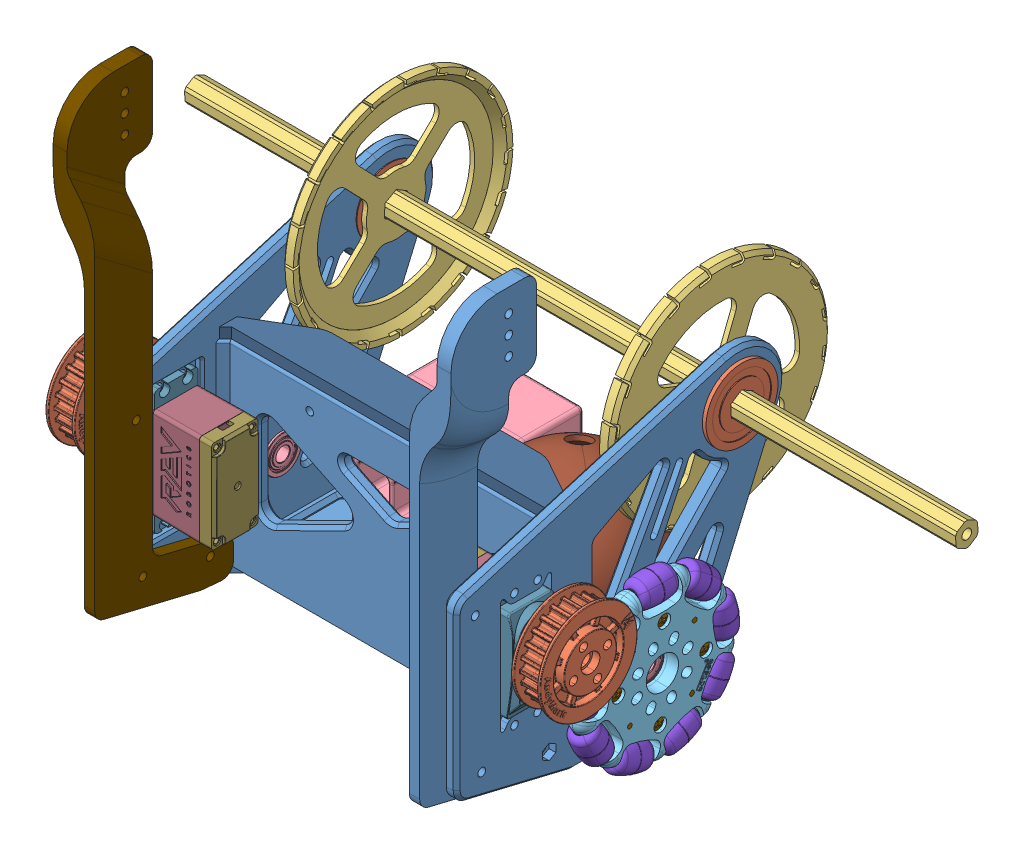
SolidWorks assembly Intake2RubberBand, configuration Default. Lengths in mm.
Overall size (333.38 218.44 194.34).
110 component instances, 23 part files, 83 mates.
Components (placement in the parent):
- IntakeWide-1: IntakeWide [Default] at (-43.2378 29.5162 123.384) size (157 122.29 142.09)
- 0_375_Hex_ID_x_1_125_OD_x_0_313_WD_Flanged_Bearing_217-2735 (1).step-1: 0_375_Hex_ID_x_1_125_OD_x_0_313_WD_Flanged_Bearing_217-2735 (1).step [Default] at (101.4122 125.5162 108.384) x (0 0.54174 -0.840546) z (0 -0.840546 -0.54174) size (31.12 7.94 31.12)
- 0_375_Hex_ID_x_1_125_OD_x_0_313_WD_Flanged_Bearing_217-2735 (1).step-2: 0_375_Hex_ID_x_1_125_OD_x_0_313_WD_Flanged_Bearing_217-2735 (1).step [Default] at (-42.8878 125.5162 108.384) x (0 0.998804 0.048888) z (0 -0.048888 0.998804) size (31.12 7.94 31.12)
- 375Hex13.3in-1: 375Hex13.3in [Default] at (-250.6814 125.5123 108.3763) x (0 0.54174 -0.840546) z (-1 0 0) size (10.24 9.53 333.38)
- 1601-0014-0006.step-1: 1601-0014-0006.step [Default] at (105.8122 54.5162 155.184) x (0 -0.381849 0.924225) z (0 -0.924225 -0.381849) size (15.95 5 15.95)
- 1601-0014-0006.step-2: 1601-0014-0006.step [Default] at (-47.2878 54.5162 155.184) x (0 -1 0) z (0 0 1) size (15.95 5 15.95)
- 3604-0014-0072 assembly.STEP-1: 3604-0014-0072 assembly.STEP [Default] at (98.0385 38.1974 184.2388) x (0 -0.339821 0.94049) z (0 0.94049 0.339821) size (78.59 16.98 77.39)
  - 3604-0014-0072 wheel half.STEP-1: 3604-0014-0072 wheel half.STEP [Default] at (-32.8712 13.6737 5.4742) size (67.84 5 66.97)
  - 3604-0014-0072 wheel half.STEP-2: 3604-0014-0072 wheel half.STEP [Default] at (-32.8712 23.6737 5.4742) x (-1 0 0) z (0 0 1) size (67.84 5 66.97)
  - 3604-0014-0072 bushing.STEP-1: 3604-0014-0072 bushing.STEP [Default] at (-52.1548 18.6737 -17.5071) x (-0.130318 0.979233 -0.155307) z (-0.766044 0 0.642788) size (5.61 5.61 17.1)
  - 3604-0014-0072 shaft.STEP-1: 3604-0014-0072 shaft.STEP [Default] at (-60.0068 18.6737 -10.9185) x (0.629069 0.205497 0.749695) z (-0.132091 0.978658 -0.15742) size (3.17 20.5 3.17)
  - 3604-0014-0072 roller.STEP-1: 3604-0014-0072 roller.STEP [Default] at (-52.1548 18.6737 -17.5071) x (-0.385664 0.800009 -0.459617) z (-0.766044 0 0.642788) size (12.13 12.13 16)
  - 3604-0014-0072 shaft.STEP-2: 3604-0014-0072 shaft.STEP [Default] at (-43.1212 18.6737 -24.5258) x (0 0.205497 0.978658) z (0 0.978658 -0.205497) size (3.17 20.5 3.17)
  - 3604-0014-0072 shaft.STEP-3: 3604-0014-0072 shaft.STEP [Default] at (-21.4395 18.6737 -24.0957) x (-0.629069 0.205497 0.749695) z (0.132091 0.978658 -0.15742) size (3.17 20.5 3.17)
  - 3604-0014-0072 shaft.STEP-4: 3604-0014-0072 shaft.STEP [Default] at (-5.1069 18.6737 -9.8295) x (-0.96379 0.205497 0.169942) z (0.202375 0.978658 -0.035684) size (3.17 20.5 3.17)
  - 3604-0014-0072 shaft.STEP-5: 3604-0014-0072 shaft.STEP [Default] at (-1.7654 18.6737 11.5975) x (-0.847543 0.205497 -0.489329) z (0.177965 0.978658 0.102748) size (3.17 20.5 3.17)
  - 3604-0014-0072 shaft.STEP-6: 3604-0014-0072 shaft.STEP [Default] at (-12.9787 18.6737 30.1593) x (-0.334721 0.205497 -0.919638) z (0.070284 0.978658 0.193104) size (3.17 20.5 3.17)
  - 3604-0014-0072 shaft.STEP-7: 3604-0014-0072 shaft.STEP [Default] at (-33.4999 18.6737 37.1707) x (0.334721 0.205497 -0.919638) z (-0.070284 0.978658 0.193104) size (3.17 20.5 3.17)
  - 3604-0014-0072 shaft.STEP-8: 3604-0014-0072 shaft.STEP [Default] at (-53.727 18.6737 29.351) x (0.847543 0.205497 -0.489329) z (-0.177965 0.978658 0.102748) size (3.17 20.5 3.17)
  - 3604-0014-0072 shaft.STEP-9: 3604-0014-0072 shaft.STEP [Default] at (-64.1953 18.6737 10.3591) x (0.96379 0.205497 0.169942) z (-0.202375 0.978658 -0.035684) size (3.17 20.5 3.17)
  - 3604-0014-0072 bushing.STEP-2: 3604-0014-0072 bushing.STEP [Default] at (-32.8712 18.6737 -24.5258) x (0 0.979233 -0.202739) z (-1 0 0) size (5.61 5.61 17.1)
  - 3604-0014-0072 bushing.STEP-3: 3604-0014-0072 bushing.STEP [Default] at (-13.5876 18.6737 -17.5071) x (0.130318 0.979233 -0.155307) z (-0.766044 0 -0.642788) size (5.61 5.61 17.1)
  - 3604-0014-0072 bushing.STEP-4: 3604-0014-0072 bushing.STEP [Default] at (-3.327 18.6737 0.2648) x (0.199659 0.979233 -0.035205) z (-0.173648 0 -0.984808) size (5.61 5.61 17.1)
  - 3604-0014-0072 bushing.STEP-5: 3604-0014-0072 bushing.STEP [Default] at (-6.8904 18.6737 20.4742) x (0.175577 0.979233 0.101369) z (0.5 0 -0.866025) size (5.61 5.61 17.1)
  - 3604-0014-0072 bushing.STEP-6: 3604-0014-0072 bushing.STEP [Default] at (-22.6106 18.6737 33.665) x (0.069341 0.979233 0.190512) z (0.939693 0 -0.34202) size (5.61 5.61 17.1)
  - 3604-0014-0072 bushing.STEP-7: 3604-0014-0072 bushing.STEP [Default] at (-43.1318 18.6737 33.665) x (-0.069341 0.979233 0.190512) z (0.939693 0 0.34202) size (5.61 5.61 17.1)
  - 3604-0014-0072 bushing.STEP-8: 3604-0014-0072 bushing.STEP [Default] at (-58.852 18.6737 20.4742) x (-0.175577 0.979233 0.101369) z (0.5 0 0.866025) size (5.61 5.61 17.1)
  - 3604-0014-0072 bushing.STEP-9: 3604-0014-0072 bushing.STEP [Default] at (-62.4154 18.6737 0.2648) x (-0.199659 0.979233 -0.035205) z (-0.173648 0 0.984808) size (5.61 5.61 17.1)
  - 3604-0014-0072 roller.STEP-2: 3604-0014-0072 roller.STEP [Default] at (-32.8712 18.6737 -24.5258) x (0 0.800009 -0.599987) z (-1 0 0) size (12.13 12.13 16)
  - 3604-0014-0072 roller.STEP-3: 3604-0014-0072 roller.STEP [Default] at (-13.5876 18.6737 -17.5071) x (0.385664 0.800009 -0.459617) z (-0.766044 0 -0.642788) size (12.13 12.13 16)
  - 3604-0014-0072 roller.STEP-4: 3604-0014-0072 roller.STEP [Default] at (-3.327 18.6737 0.2648) x (0.590872 0.800009 -0.104187) z (-0.173648 0 -0.984808) size (12.13 12.13 16)
  - 3604-0014-0072 roller.STEP-5: 3604-0014-0072 roller.STEP [Default] at (-6.8904 18.6737 20.4742) x (0.519604 0.800009 0.299994) z (0.5 0 -0.866025) size (12.13 12.13 16)
  - 3604-0014-0072 roller.STEP-6: 3604-0014-0072 roller.STEP [Default] at (-22.6106 18.6737 33.665) x (0.205208 0.800009 0.563804) z (0.939693 0 -0.34202) size (12.13 12.13 16)
  - 3604-0014-0072 roller.STEP-7: 3604-0014-0072 roller.STEP [Default] at (-43.1318 18.6737 33.665) x (-0.205208 0.800009 0.563804) z (0.939693 0 0.34202) size (12.13 12.13 16)
  - 3604-0014-0072 roller.STEP-8: 3604-0014-0072 roller.STEP [Default] at (-58.852 18.6737 20.4742) x (-0.519604 0.800009 0.299994) z (0.5 0 0.866025) size (12.13 12.13 16)
  - 3604-0014-0072 roller.STEP-9: 3604-0014-0072 roller.STEP [Default] at (-62.4154 18.6737 0.2648) x (-0.590872 0.800009 -0.104187) z (-0.173648 0 0.984808) size (12.13 12.13 16)
  - 364 omni wheel screw_99461A110.STEP-1: 364 omni wheel screw_99461A110.STEP [Default] at (-40.1422 17.6737 23.0279) x (1 0 0) z (0 1 0) size (5.22 5.22 9.61)
  - 364 omni wheel screw_99461A110.STEP-2: 364 omni wheel screw_99461A110.STEP [Default] at (-50.4249 17.6737 -1.7968) x (0 0 1) z (0 1 0) size (5.22 5.22 9.61)
  - 364 omni wheel screw_99461A110.STEP-3: 364 omni wheel screw_99461A110.STEP [Default] at (-25.6002 17.6737 -12.0795) x (-1 0 0) z (0 1 0) size (5.22 5.22 9.61)
  - 364 omni wheel screw_99461A110.STEP-4: 364 omni wheel screw_99461A110.STEP [Default] at (-15.3175 17.6737 12.7452) x (0 0 -1) z (0 1 0) size (5.22 5.22 9.61)
  - 364 omni wheel screw_99461A110.STEP-5: 364 omni wheel screw_99461A110.STEP [Default] at (-25.6002 19.6737 23.0279) x (-0.837169 0 -0.546944) z (0 -1 0) size (5.22 5.22 9.61)
  - 364 omni wheel screw_99461A110.STEP-6: 364 omni wheel screw_99461A110.STEP [Default] at (-15.3175 19.6737 -1.7968) x (-0.546944 0 0.837169) z (0 -1 0) size (5.22 5.22 9.61)
  - 364 omni wheel screw_99461A110.STEP-7: 364 omni wheel screw_99461A110.STEP [Default] at (-40.1422 19.6737 -12.0795) x (0.837169 0 0.546944) z (0 -1 0) size (5.22 5.22 9.61)
  - 364 omni wheel screw_99461A110.STEP-8: 364 omni wheel screw_99461A110.STEP [Default] at (-50.4249 19.6737 12.7452) x (0.546944 0 -0.837169) z (0 -1 0) size (5.22 5.22 9.61)
- 1601-0014-0006.step-6: 1601-0014-0006.step [Default] at (115.7622 54.5162 155.184) x (0 -0.381849 0.924225) z (0 -0.924225 -0.381849) size (15.95 5 15.95)
- 1601-0014-0006.step-8: 1601-0014-0006.step [Default] at (-58.1878 54.5162 155.184) x (0 0.206987 0.978344) z (0 -0.978344 0.206987) size (15.95 5 15.95)
- 3604-0014-0072 assembly.STEP-2: 3604-0014-0072 assembly.STEP [Default] at (-75.9115 38.6322 184.4787) x (0 -0.32577 0.945449) z (0 0.945449 0.32577) size (78.59 16.98 77.39)
  - 3604-0014-0072 wheel half.STEP-1: 3604-0014-0072 wheel half.STEP [Default] at (-32.8712 13.6737 5.4742) size (67.84 5 66.97)
  - 3604-0014-0072 wheel half.STEP-2: 3604-0014-0072 wheel half.STEP [Default] at (-32.8712 23.6737 5.4742) x (-1 0 0) z (0 0 1) size (67.84 5 66.97)
  - 3604-0014-0072 bushing.STEP-1: 3604-0014-0072 bushing.STEP [Default] at (-52.1548 18.6737 -17.5071) x (-0.130318 0.979233 -0.155307) z (-0.766044 0 0.642788) size (5.61 5.61 17.1)
  - 3604-0014-0072 shaft.STEP-1: 3604-0014-0072 shaft.STEP [Default] at (-60.0068 18.6737 -10.9185) x (0.629069 0.205497 0.749695) z (-0.132091 0.978658 -0.15742) size (3.17 20.5 3.17)
  - 3604-0014-0072 roller.STEP-1: 3604-0014-0072 roller.STEP [Default] at (-52.1548 18.6737 -17.5071) x (-0.385664 0.800009 -0.459617) z (-0.766044 0 0.642788) size (12.13 12.13 16)
  - 3604-0014-0072 shaft.STEP-2: 3604-0014-0072 shaft.STEP [Default] at (-43.1212 18.6737 -24.5258) x (0 0.205497 0.978658) z (0 0.978658 -0.205497) size (3.17 20.5 3.17)
  - 3604-0014-0072 shaft.STEP-3: 3604-0014-0072 shaft.STEP [Default] at (-21.4395 18.6737 -24.0957) x (-0.629069 0.205497 0.749695) z (0.132091 0.978658 -0.15742) size (3.17 20.5 3.17)
  - 3604-0014-0072 shaft.STEP-4: 3604-0014-0072 shaft.STEP [Default] at (-5.1069 18.6737 -9.8295) x (-0.96379 0.205497 0.169942) z (0.202375 0.978658 -0.035684) size (3.17 20.5 3.17)
  - 3604-0014-0072 shaft.STEP-5: 3604-0014-0072 shaft.STEP [Default] at (-1.7654 18.6737 11.5975) x (-0.847543 0.205497 -0.489329) z (0.177965 0.978658 0.102748) size (3.17 20.5 3.17)
  - 3604-0014-0072 shaft.STEP-6: 3604-0014-0072 shaft.STEP [Default] at (-12.9787 18.6737 30.1593) x (-0.334721 0.205497 -0.919638) z (0.070284 0.978658 0.193104) size (3.17 20.5 3.17)
  - 3604-0014-0072 shaft.STEP-7: 3604-0014-0072 shaft.STEP [Default] at (-33.4999 18.6737 37.1707) x (0.334721 0.205497 -0.919638) z (-0.070284 0.978658 0.193104) size (3.17 20.5 3.17)
  - 3604-0014-0072 shaft.STEP-8: 3604-0014-0072 shaft.STEP [Default] at (-53.727 18.6737 29.351) x (0.847543 0.205497 -0.489329) z (-0.177965 0.978658 0.102748) size (3.17 20.5 3.17)
  - 3604-0014-0072 shaft.STEP-9: 3604-0014-0072 shaft.STEP [Default] at (-64.1953 18.6737 10.3591) x (0.96379 0.205497 0.169942) z (-0.202375 0.978658 -0.035684) size (3.17 20.5 3.17)
  - 3604-0014-0072 bushing.STEP-2: 3604-0014-0072 bushing.STEP [Default] at (-32.8712 18.6737 -24.5258) x (0 0.979233 -0.202739) z (-1 0 0) size (5.61 5.61 17.1)
  - 3604-0014-0072 bushing.STEP-3: 3604-0014-0072 bushing.STEP [Default] at (-13.5876 18.6737 -17.5071) x (0.130318 0.979233 -0.155307) z (-0.766044 0 -0.642788) size (5.61 5.61 17.1)
  - 3604-0014-0072 bushing.STEP-4: 3604-0014-0072 bushing.STEP [Default] at (-3.327 18.6737 0.2648) x (0.199659 0.979233 -0.035205) z (-0.173648 0 -0.984808) size (5.61 5.61 17.1)
  - 3604-0014-0072 bushing.STEP-5: 3604-0014-0072 bushing.STEP [Default] at (-6.8904 18.6737 20.4742) x (0.175577 0.979233 0.101369) z (0.5 0 -0.866025) size (5.61 5.61 17.1)
  - 3604-0014-0072 bushing.STEP-6: 3604-0014-0072 bushing.STEP [Default] at (-22.6106 18.6737 33.665) x (0.069341 0.979233 0.190512) z (0.939693 0 -0.34202) size (5.61 5.61 17.1)
  - 3604-0014-0072 bushing.STEP-7: 3604-0014-0072 bushing.STEP [Default] at (-43.1318 18.6737 33.665) x (-0.069341 0.979233 0.190512) z (0.939693 0 0.34202) size (5.61 5.61 17.1)
  - 3604-0014-0072 bushing.STEP-8: 3604-0014-0072 bushing.STEP [Default] at (-58.852 18.6737 20.4742) x (-0.175577 0.979233 0.101369) z (0.5 0 0.866025) size (5.61 5.61 17.1)
  - 3604-0014-0072 bushing.STEP-9: 3604-0014-0072 bushing.STEP [Default] at (-62.4154 18.6737 0.2648) x (-0.199659 0.979233 -0.035205) z (-0.173648 0 0.984808) size (5.61 5.61 17.1)
  - 3604-0014-0072 roller.STEP-2: 3604-0014-0072 roller.STEP [Default] at (-32.8712 18.6737 -24.5258) x (0 0.800009 -0.599987) z (-1 0 0) size (12.13 12.13 16)
  - 3604-0014-0072 roller.STEP-3: 3604-0014-0072 roller.STEP [Default] at (-13.5876 18.6737 -17.5071) x (0.385664 0.800009 -0.459617) z (-0.766044 0 -0.642788) size (12.13 12.13 16)
  - 3604-0014-0072 roller.STEP-4: 3604-0014-0072 roller.STEP [Default] at (-3.327 18.6737 0.2648) x (0.590872 0.800009 -0.104187) z (-0.173648 0 -0.984808) size (12.13 12.13 16)
  - 3604-0014-0072 roller.STEP-5: 3604-0014-0072 roller.STEP [Default] at (-6.8904 18.6737 20.4742) x (0.519604 0.800009 0.299994) z (0.5 0 -0.866025) size (12.13 12.13 16)
  - 3604-0014-0072 roller.STEP-6: 3604-0014-0072 roller.STEP [Default] at (-22.6106 18.6737 33.665) x (0.205208 0.800009 0.563804) z (0.939693 0 -0.34202) size (12.13 12.13 16)
  - 3604-0014-0072 roller.STEP-7: 3604-0014-0072 roller.STEP [Default] at (-43.1318 18.6737 33.665) x (-0.205208 0.800009 0.563804) z (0.939693 0 0.34202) size (12.13 12.13 16)
  - 3604-0014-0072 roller.STEP-8: 3604-0014-0072 roller.STEP [Default] at (-58.852 18.6737 20.4742) x (-0.519604 0.800009 0.299994) z (0.5 0 0.866025) size (12.13 12.13 16)
  - 3604-0014-0072 roller.STEP-9: 3604-0014-0072 roller.STEP [Default] at (-62.4154 18.6737 0.2648) x (-0.590872 0.800009 -0.104187) z (-0.173648 0 0.984808) size (12.13 12.13 16)
  - 364 omni wheel screw_99461A110.STEP-1: 364 omni wheel screw_99461A110.STEP [Default] at (-40.1422 17.6737 23.0279) x (1 0 0) z (0 1 0) size (5.22 5.22 9.61)
  - 364 omni wheel screw_99461A110.STEP-2: 364 omni wheel screw_99461A110.STEP [Default] at (-50.4249 17.6737 -1.7968) x (0 0 1) z (0 1 0) size (5.22 5.22 9.61)
  - 364 omni wheel screw_99461A110.STEP-3: 364 omni wheel screw_99461A110.STEP [Default] at (-25.6002 17.6737 -12.0795) x (-1 0 0) z (0 1 0) size (5.22 5.22 9.61)
  - 364 omni wheel screw_99461A110.STEP-4: 364 omni wheel screw_99461A110.STEP [Default] at (-15.3175 17.6737 12.7452) x (0 0 -1) z (0 1 0) size (5.22 5.22 9.61)
  - 364 omni wheel screw_99461A110.STEP-5: 364 omni wheel screw_99461A110.STEP [Default] at (-25.6002 19.6737 23.0279) x (-0.837169 0 -0.546944) z (0 -1 0) size (5.22 5.22 9.61)
  - 364 omni wheel screw_99461A110.STEP-6: 364 omni wheel screw_99461A110.STEP [Default] at (-15.3175 19.6737 -1.7968) x (-0.546944 0 0.837169) z (0 -1 0) size (5.22 5.22 9.61)
  - 364 omni wheel screw_99461A110.STEP-7: 364 omni wheel screw_99461A110.STEP [Default] at (-40.1422 19.6737 -12.0795) x (0.837169 0 0.546944) z (0 -1 0) size (5.22 5.22 9.61)
  - 364 omni wheel screw_99461A110.STEP-8: 364 omni wheel screw_99461A110.STEP [Default] at (-50.4249 19.6737 12.7452) x (0.546944 0 -0.837169) z (0 -1 0) size (5.22 5.22 9.61)
- RubberBandRoof-1: RubberBandRoof [Default] at (-43.2378 110.5162 123.384) x (1 0 0) z (0 1 0) size (145 22 18.5)
- am-2850 wiffle base Ball.step-1: am-2850 wiffle base Ball.step [Default] at (66.2022 65.0762 138.624) x (0.76558 0.27445 0.581863) z (-0.623857 0.095806 0.775644) size (71.12 71.12 71.12)
- REV-41-1097.STEP-1: REV-41-1097.STEP [Default] at (-16.8878 77.7662 200.1841) x (0 0 1) z (1 0 0) size (24.05 54 43.73)
  - A.STEP-1: A.STEP [Default] at origin size (20.15 40.13 8.54)
  - E.STEP-1: E.STEP [Default] at origin size (20.15 40.15 20.1)
  - C.STEP-1: C.STEP [Default] at origin size (24.05 54 13.28)
  - B.STEP-1: B.STEP [Default] at origin size (9 9 4.4)
  - D.STEP-1: D.STEP [Default] at (0 -10.0526 -30.1) x (-1 0 0) z (0 0 1) size (17.21 17.2 14.7)
- REV-41-1097.STEP-2: REV-41-1097.STEP [Default] at (75.4122 77.7662 200.1835) x (0 0 -1) z (-1 0 0) size (24.05 54 43.73)
  - A.STEP-1: A.STEP [Default] at origin size (20.15 40.13 8.54)
  - E.STEP-1: E.STEP [Default] at origin size (20.15 40.15 20.1)
  - C.STEP-1: C.STEP [Default] at origin size (24.05 54 13.28)
  - B.STEP-1: B.STEP [Default] at origin size (9 9 4.4)
  - D.STEP-1: D.STEP [Default] at (0 -10.0526 -30.1) x (-1 0 0) z (0 0 1) size (17.21 17.2 14.7)
- IntakeServoHorn-1: IntakeServoHorn [Default] at (-58.5878 87.8188 200.1841) x (0 0.715777 -0.698329) z (0 0.698329 0.715777) size (25 6 25)
- IntakeServoHorn-2: IntakeServoHorn [Default] at (117.1122 87.8188 200.1835) x (0 0.059406 -0.998234) z (0 -0.998234 -0.059406) size (25 6 25)
- Part2^Intake2RubberBand-1: Part2^Intake2RubberBand [Default] at (-43.2378 29.5162 123.384) x (0 0 -1) z (1 0 0) size (60 201.86 19.65) (virtual)
- IntakeArm2Mir-1: IntakeArm2Mir [Default] at (92.7622 29.5162 123.384) x (0 0 -1) z (1 0 0) size (60 201.86 19.65)
- am-3401+24+tooth+HTD+pulley+half+6mm+bore-1: am-3401+24+tooth+HTD+pulley+half+6mm+bore [Default] at (-70.0903 76.941 175.3595) x (-1 0 0) z (0 -0.924225 -0.381849) size (8.91 42 42)
- am-3401+24+tooth+HTD+pulley+half+6mm+bore-2: am-3401+24+tooth+HTD+pulley+half+6mm+bore [Default] at (-70.0903 60.9034 214.1769) x (1 0 0) z (0 -0.924225 -0.381849) size (8.91 42 42)
- am-3401+24+tooth+HTD+pulley+half+6mm+bore-3: am-3401+24+tooth+HTD+pulley+half+6mm+bore [Default] at (128.6147 60.3913 211.5733) x (1 0 0) z (0 -0.924225 -0.381849) size (8.91 42 42)
- am-3401+24+tooth+HTD+pulley+half+6mm+bore-4: am-3401+24+tooth+HTD+pulley+half+6mm+bore [Default] at (128.6147 76.4289 172.7559) x (-1 0 0) z (0 -0.924225 -0.381849) size (8.91 42 42)
- Part1^Intake2RubberBand-1: Part1^Intake2RubberBand [Default] at origin (virtual)
- IntakeBandWheel-1: IntakeBandWheel [Default] at (100.2333 125.5162 108.384) x (-1 0 0) z (0 -0.91644 -0.400173) size (5 94.99 94.99)
- IntakeBandWheel-2: IntakeBandWheel [Default] at (-42.2378 125.5162 108.384) x (1 0 0) z (0 0.019908 0.999802) size (5 94.99 94.99)
- ftc-2013 2in Cube.step-2: ftc-2013 2in Cube.step [Default] at (5.2422 54.9162 123.3042) size (50.8 50.8 50.94)
Mates (geometry in assembly coordinates):
- Concentric1: concentric: cylinder of IntakeWide-1 through (101.7622 125.5162 108.384) axis (1 0 0) radius 14.2875; cylinder of 0_375_Hex_ID_x_1_125_OD_x_0_313_WD_Flanged_Bearing_217-2735 (1).step-1 through (101.4122 125.5162 108.384) axis (1 0 0) radius 14.2748
- Coincident1: coincident: plane of IntakeWide-1 through (107.7622 23.5162 174.184) normal (1 0 0); plane of 0_375_Hex_ID_x_1_125_OD_x_0_313_WD_Flanged_Bearing_217-2735 (1).step-1 through (107.7622 133.9444 95.3072) normal (-1 0 0)
- Concentric2: concentric: cylinder of IntakeWide-1 through (-43.2378 125.5162 108.384) axis (-1 0 0) radius 14.2875; cylinder of 0_375_Hex_ID_x_1_125_OD_x_0_313_WD_Flanged_Bearing_217-2735 (1).step-2 through (-42.8878 125.5162 108.384) axis (-1 0 0) radius 14.2748
- Coincident2: coincident: plane of IntakeWide-1 through (-49.2378 23.5162 174.184) normal (-1 0 0); plane of 0_375_Hex_ID_x_1_125_OD_x_0_313_WD_Flanged_Bearing_217-2735 (1).step-2 through (-49.2378 141.0551 109.1446) normal (1 0 0)
- Coincident3: coincident: plane of 0_375_Hex_ID_x_1_125_OD_x_0_313_WD_Flanged_Bearing_217-2735 (1).step-1 through (127.3102 122.9988 103.4851) normal (0 0.840546 0.54174); plane of 375Hex13.3in-1 through (-707.8814 122.9988 103.4851) normal (0 -0.840546 -0.54174)
- Coincident4: coincident: plane of 0_375_Hex_ID_x_1_125_OD_x_0_313_WD_Flanged_Bearing_217-2735 (1).step-2 through (-68.7858 120.0149 108.1147) normal (0 0.840546 0.54174); plane of 375Hex13.3in-1 through (-707.8814 122.9988 103.4851) normal (0 -0.840546 -0.54174)
- Coincident5: coincident: plane of 0_375_Hex_ID_x_1_125_OD_x_0_313_WD_Flanged_Bearing_217-2735 (1).step-1 through (127.3102 128.5001 103.7544) normal (0 -0.048888 0.998804); plane of 375Hex13.3in-1 through (-707.8814 128.4914 103.7539) normal (0 0.048888 -0.998804)
- Concentric3: concentric: cylinder of IntakeWide-1 through (-49.2378 54.5162 155.184) axis (1 0 0) radius 7.05; cylinder of 1601-0014-0006.step-1 through (101.7622 54.5162 155.184) axis (1 0 0) radius 7
- Coincident6: coincident: plane of IntakeWide-1 through (101.7622 29.5162 174.184) normal (-1 0 0); plane of 1601-0014-0006.step-1 through (101.7622 54.5162 155.184) normal (1 0 0)
- Coincident7: coincident: plane of IntakeWide-1 through (-43.2378 29.5162 174.184) normal (1 0 0); plane of 1601-0014-0006.step-2 through (-43.2378 54.5162 155.184) normal (-1 0 0)
- Concentric4: concentric: cylinder of IntakeWide-1 through (-49.2378 54.5162 155.184) axis (1 0 0) radius 7.05; cylinder of 1601-0014-0006.step-2 through (-43.2378 54.5162 155.184) axis (-1 0 0) radius 7
- Coincident8: coincident: circle of 3604-0014-0072 assembly.STEP-1/3604-0014-0072 wheel half.STEP-2; cylinder of ? through (121.7122 54.5162 155.184) axis (-1 0 0) radius 7
- Coincident9: coincident: plane of 3604-0014-0072 assembly.STEP-1/3604-0014-0072 wheel half.STEP-2 through (121.7122 54.5162 155.184) normal (1 0 0); plane of ? through (121.7122 54.5162 155.184) normal (-1 0 0)
- Concentric5: concentric: cylinder of 3604-0014-0072 assembly.STEP-1/3604-0014-0072 wheel half.STEP-1 through (111.7122 54.5162 155.184) axis (1 0 0) radius 7; cylinder of 1601-0014-0006.step-6 through (111.7122 54.5162 155.184) axis (1 0 0) radius 7
- Coincident10: coincident: plane of 3604-0014-0072 assembly.STEP-1/3604-0014-0072 wheel half.STEP-1 through (111.7122 54.5162 155.184) normal (-1 0 0); plane of 1601-0014-0006.step-6 through (111.7122 54.5162 155.184) normal (1 0 0)
- Concentric6: concentric: cylinder of 1601-0014-0006.step-1 through (105.8122 54.5162 155.184) axis (-1 0 0) radius 3; cylinder of ? through (117.6622 54.5162 155.184) axis (1 0 0) radius 3
- Distance2: distance = 3 mm: plane of 1601-0014-0006.step-6 through (110.7622 54.5162 155.184) normal (-1 0 0); plane of IntakeWide-1 through (107.7622 23.5162 174.184) normal (1 0 0)
- Concentric7: concentric: cylinder of ? through (-62.2378 54.5162 155.184) axis (1 0 0) radius 7; cylinder of 3604-0014-0072 assembly.STEP-2/3604-0014-0072 wheel half.STEP-1 through (-62.2378 54.5162 155.184) axis (1 0 0) radius 7
- Coincident13: coincident: cylinder of 1601-0014-0006.step-8 through (-62.2378 54.5162 155.184) axis (1 0 0) radius 7; circle of 3604-0014-0072 assembly.STEP-2/3604-0014-0072 wheel half.STEP-2
- Coincident14: coincident: plane of 1601-0014-0006.step-8 through (-62.2378 54.5162 155.184) normal (1 0 0); plane of 3604-0014-0072 assembly.STEP-2/3604-0014-0072 wheel half.STEP-1 through (-62.2378 54.5162 155.184) normal (-1 0 0)
- Coincident15: coincident: plane of ? through (-62.2378 54.5162 155.184) normal (1 0 0); plane of 3604-0014-0072 assembly.STEP-2/3604-0014-0072 wheel half.STEP-1 through (-62.2378 54.5162 155.184) normal (-1 0 0)
- Concentric8: concentric: cylinder of 1601-0014-0006.step-2 through (-47.2878 54.5162 155.184) axis (1 0 0) radius 3; cylinder of ? through (-58.1878 54.5162 155.184) axis (-1 0 0) radius 3
- Distance3: distance = 3 mm: plane of 3604-0014-0072 assembly.STEP-2/3604-0014-0072 wheel half.STEP-2 through (-52.2378 54.5162 155.184) normal (1 0 0); plane of IntakeWide-1 through (-49.2378 23.5162 174.184) normal (-1 0 0)
- Coincident17: coincident: plane of 375Hex13.3in-1 through (-707.8814 128.4914 103.7539) normal (0 0.048888 -0.998804); plane of ? through (79.2622 128.4914 103.7539) normal (0 -0.048888 0.998804)
- Coincident18: coincident: plane of 375Hex13.3in-1 through (-707.8814 122.9988 103.4851) normal (0 -0.840546 -0.54174); plane of ? through (79.2622 122.9988 103.4851) normal (0 0.840546 0.54174)
- Coincident19: coincident: plane of 375Hex13.3in-1 through (-707.8814 122.5331 112.9987) normal (0 -0.048888 0.998804); plane of ? through (39.2622 122.5331 112.9987) normal (0 0.048888 -0.998804)
- Coincident20: coincident: plane of 375Hex13.3in-1 through (-707.8814 122.5331 112.9987) normal (0 -0.048888 0.998804); plane of ? through (-0.7378 122.5331 112.9987) normal (0 0.048888 -0.998804)
- Coincident21: coincident: plane of 375Hex13.3in-1 through (-707.8814 122.5331 112.9987) normal (0 -0.048888 0.998804); plane of ? through (-40.7378 122.5331 112.9987) normal (0 0.048888 -0.998804)
- Coincident22: coincident: plane of 375Hex13.3in-1 through (-707.8814 128.0258 113.2675) normal (0 0.840546 0.54174); plane of ? through (39.2622 128.0258 113.2675) normal (0 -0.840546 -0.54174)
- Coincident23: coincident: plane of 375Hex13.3in-1 through (-707.8814 128.0258 113.2675) normal (0 0.840546 0.54174); plane of ? through (-0.7378 128.0258 113.2675) normal (0 -0.840546 -0.54174)
- Coincident24: coincident: plane of 375Hex13.3in-1 through (-707.8814 122.9988 103.4851) normal (0 -0.840546 -0.54174); plane of ? through (-40.7378 122.9988 103.4851) normal (0 0.840546 0.54174)
- Distance4: distance = 20 mm: plane of ? through (59.2622 125.5123 108.3763) normal (1 0 0); plane of ? through (79.2622 125.5123 108.3763) normal (-1 0 0)
- Distance5: distance = 20 mm: plane of ? through (39.2622 125.5123 108.3763) normal (-1 0 0); plane of ? through (19.2622 125.5123 108.3763) normal (1 0 0)
- Distance6: distance = 20 mm: plane of ? through (-20.7378 125.5123 108.3763) normal (1 0 0); plane of ? through (-0.7378 125.5123 108.3763) normal (-1 0 0)
- Distance7: distance = 2.5 mm: plane of IntakeWide-1 through (101.7622 29.5162 174.184) normal (-1 0 0); plane of ? through (99.2622 125.5123 108.3763) normal (1 0 0)
- InPlace1: in place: plane of IntakeWide-1 through (-49.2378 110.5162 174.184) normal (0 1 0); plane of ? through (0 110.5162 0) normal (0 1 0); moOrthogonalPlaneRef_w of IntakeWide-1 through (-49.2378 110.5162 174.184) normal (0 1 0); plane of ? through (0 110.5162 0) normal (0 0 -1); plane of IntakeWide-1 through (-49.2378 110.5162 174.184) normal (0 1 0); plane of ? through (0 110.5162 0) normal (1 0 0); plane of IntakeWide-1 through (-49.2378 110.5162 174.184) normal (0 1 0); unknown of RubberBandRoof-1
- Coincident29: coincident: plane of IntakeWide-1; plane of RubberBandRoof-1
- Coincident30: coincident: moOrthogonalPlaneRef_w of IntakeWide-1 through (-43.2378 110.5162 123.384) normal (0 0 -1); plane of RubberBandRoof-1 through (-43.2378 110.5162 123.384) normal (0 0 -1)
- Coincident31: coincident: moOrthogonalPlaneRef_w of IntakeWide-1 through (-43.2378 110.5162 123.384) normal (-1 0 0); plane of RubberBandRoof-1 through (-43.2378 110.5162 123.384) normal (1 0 0)
- Tangent1: tangent: plane of IntakeWide-1 through (-43.2378 29.5162 174.184) normal (0 1 0); sphere of am-2850 wiffle base Ball.step-1
- Tangent2: tangent: plane of IntakeWide-1 through (-43.2378 29.5162 174.184) normal (0 0 -1); sphere of am-2850 wiffle base Ball.step-1
- Tangent3: tangent: plane of IntakeWide-1 through (101.7622 29.5162 174.184) normal (-1 0 0); sphere of am-2850 wiffle base Ball.step-1
- Coincident32: coincident: plane of IntakeWide-1 through (-43.2378 29.5162 174.184) normal (0 1 0); plane of ? through (27.6547 29.5162 120.384) normal (0 -1 0)
- Distance8: distance = 3 mm: plane of ? through (-23.1453 80.3162 171.184) normal (0 0 1); plane of IntakeWide-1 through (-43.2378 29.5162 174.184) normal (0 0 -1)
- Concentric9: concentric: cylinder of IntakeWide-1 through (-43.2378 102.5162 205.1841) axis (-1 0 0) radius 1.65; cylinder of REV-41-1097.STEP-1/C.STEP-1 through (-46.2378 102.5162 205.1841) axis (-1 0 0) radius 2.25
- Concentric10: concentric: cylinder of IntakeWide-1 through (-43.2378 102.5162 195.1835) axis (-1 0 0) radius 1.65; cylinder of REV-41-1097.STEP-1/C.STEP-1 through (-46.2378 102.5162 195.1841) axis (-1 0 0) radius 2.25
- Concentric11: concentric: cylinder of IntakeWide-1 through (101.7622 102.5162 195.1835) axis (1 0 0) radius 1.65; cylinder of REV-41-1097.STEP-2/C.STEP-1 through (104.7622 102.5162 195.1835) axis (1 0 0) radius 2.25
- Concentric12: concentric: cylinder of IntakeWide-1 through (101.7622 102.5162 205.1841) axis (1 0 0) radius 1.65; cylinder of REV-41-1097.STEP-2/C.STEP-1 through (104.7622 102.5162 205.1835) axis (1 0 0) radius 2.25
- Coincident34: coincident: plane of IntakeWide-1 through (104.7622 29.5162 123.384) normal (-1 0 0); plane of REV-41-1097.STEP-2/C.STEP-1 through (104.7622 77.7662 200.1835) normal (1 0 0)
- Concentric13: concentric: circle of REV-41-1097.STEP-1/D.STEP-1; cylinder of IntakeServoHorn-1 through (-63.0878 87.8188 200.1841) axis (1 0 0) radius 1.75
- Coincident35: coincident: plane of REV-41-1097.STEP-1/D.STEP-1 through (-60.5878 87.8188 200.1841) normal (-1 0 0); plane of IntakeServoHorn-1 through (-60.5878 87.8188 200.1841) normal (1 0 0)
- Concentric14: concentric: circle of REV-41-1097.STEP-2/D.STEP-1; cylinder of IntakeServoHorn-2 through (119.1122 87.8188 200.1835) axis (1 0 0) radius 12.5
- Coincident36: coincident: plane of REV-41-1097.STEP-2/D.STEP-1 through (119.1122 87.8188 200.1835) normal (1 0 0); plane of IntakeServoHorn-2 through (119.1122 87.8188 200.1835) normal (-1 0 0)
- BeltMate1: belt = 4.2 : 25 mm: circle of IntakeServoHorn-1; cylinder of 375Hex13.3in-1 through (206.5186 125.5123 108.3763) axis (-1 0 0) radius 2.1
- InPlace2: in place: plane of IntakeWide-1 through (-43.2378 29.5162 174.184) normal (1 0 0); plane of ? through (-43.2378 0 0) normal (1 0 0); plane of IntakeWide-1 through (-43.2378 29.5162 174.184) normal (1 0 0); plane of ? through (-43.2378 0 0) normal (0 1 0); plane of IntakeWide-1 through (-43.2378 29.5162 174.184) normal (1 0 0); plane of ? through (-43.2378 0 0) normal (0 0 -1); plane of IntakeWide-1 through (-43.2378 29.5162 174.184) normal (1 0 0); unknown of Part2^Intake2RubberBand-1
- Coincident37: coincident: plane of IntakeWide-1; plane of ?
- Coincident38: coincident: moOrthogonalPlaneRef_w of IntakeWide-1 through (-43.2378 29.5162 123.384) normal (0 1 0); plane of Part2^Intake2RubberBand-1 through (-43.2378 29.5162 123.384) normal (0 1 0)
- Coincident39: coincident: moOrthogonalPlaneRef_w of IntakeWide-1 through (-43.2378 29.5162 123.384) normal (0 0 1); plane of Part2^Intake2RubberBand-1 through (-43.2378 29.5162 123.384) normal (0 0 -1)
- InPlace3: in place: plane of IntakeWide-1 through (-43.2378 29.5162 174.184) normal (1 0 0); plane of ? through (-43.2378 0 0) normal (1 0 0); plane of IntakeWide-1 through (-43.2378 29.5162 174.184) normal (1 0 0); plane of ? through (-43.2378 0 0) normal (0 1 0); plane of IntakeWide-1 through (-43.2378 29.5162 174.184) normal (1 0 0); plane of ? through (-43.2378 0 0) normal (0 0 -1); plane of IntakeWide-1 through (-43.2378 29.5162 174.184) normal (1 0 0); unknown of Part2^Intake2RubberBand-1
- Coincident37: coincident: plane of IntakeWide-1; plane of Part2^Intake2RubberBand-1
- Coincident38: coincident: moOrthogonalPlaneRef_w of IntakeWide-1 through (-43.2378 29.5162 123.384) normal (0 1 0); plane of Part2^Intake2RubberBand-1 through (-43.2378 29.5162 123.384) normal (0 1 0)
- Coincident39: coincident: moOrthogonalPlaneRef_w of IntakeWide-1 through (-43.2378 29.5162 123.384) normal (0 0 1); plane of Part2^Intake2RubberBand-1 through (-43.2378 29.5162 123.384) normal (0 0 -1)
- Concentric15: concentric: cylinder of IntakeWide-1 through (107.7622 42.5174 219.3556) axis (-1 0 0) radius 1.7; cylinder of IntakeArm2Mir-1 through (97.2622 42.5174 219.3556) axis (1 0 0) radius 1.7
- Concentric16: concentric: cylinder of IntakeWide-1 through (107.7622 102.5162 222.184) axis (-1 0 0) radius 1.7; cylinder of IntakeArm2Mir-1 through (97.2622 102.5162 222.184) axis (1 0 0) radius 1.7
- Coincident40: coincident: plane of IntakeWide-1 through (101.7622 29.5162 174.184) normal (-1 0 0); plane of IntakeArm2Mir-1 through (101.7622 29.5162 123.384) normal (1 0 0)
- Coincident42: coincident: plane of IntakeWide-1 through (-46.2378 29.5162 123.384) normal (1 0 0); plane of REV-41-1097.STEP-1/C.STEP-1 through (-46.2378 77.7662 200.1841) normal (-1 0 0)
- Coincident43: coincident: plane of IntakeServoHorn-1 through (-63.0878 87.8188 200.1841) normal (-1 0 0); plane of am-3401+24+tooth+HTD+pulley+half+6mm+bore-1 through (-63.0878 88.3309 202.787) normal (1 0 0)
- Concentric17: concentric: cylinder of am-3401+24+tooth+HTD+pulley+half+6mm+bore-1 through (-71.9953 88.3309 202.787) axis (1 0 0) radius 3.1; cylinder of am-3401+24+tooth+HTD+pulley+half+6mm+bore-2 through (-68.1853 88.3309 202.787) axis (-1 0 0) radius 3.1
- Coincident44: coincident: plane of am-3401+24+tooth+HTD+pulley+half+6mm+bore-1 through (-70.0903 95.0374 186.2306) normal (-1 0 0); plane of am-3401+24+tooth+HTD+pulley+half+6mm+bore-2 through (-70.0903 81.3956 219.2489) normal (1 0 0)
- Concentric18: concentric: cylinder of am-3401+24+tooth+HTD+pulley+half+6mm+bore-1 through (-71.9953 95.7256 205.8422) axis (1 0 0) radius 1.778; cylinder of am-3401+24+tooth+HTD+pulley+half+6mm+bore-2 through (-68.1853 95.7256 205.8422) axis (-1 0 0) radius 1.778
- Coincident45: coincident: plane of am-3401+24+tooth+HTD+pulley+half+6mm+bore-3 through (128.6147 80.8836 216.6454) normal (1 0 0); plane of am-3401+24+tooth+HTD+pulley+half+6mm+bore-4 through (128.6147 94.5253 183.627) normal (-1 0 0)
- Concentric19: concentric: cylinder of am-3401+24+tooth+HTD+pulley+half+6mm+bore-3 through (130.5197 87.8188 200.1835) axis (-1 0 0) radius 3.1; cylinder of am-3401+24+tooth+HTD+pulley+half+6mm+bore-4 through (126.7097 87.8188 200.1835) axis (1 0 0) radius 3.1
- Concentric20: concentric: cylinder of am-3401+24+tooth+HTD+pulley+half+6mm+bore-3 through (130.5197 95.2135 203.2386) axis (-1 0 0) radius 1.778; cylinder of am-3401+24+tooth+HTD+pulley+half+6mm+bore-4 through (126.7097 95.2135 203.2386) axis (1 0 0) radius 1.778
- Concentric21: concentric: cylinder of IntakeServoHorn-2 through (121.6122 87.8188 200.1835) axis (-1 0 0) radius 1.75; cylinder of am-3401+24+tooth+HTD+pulley+half+6mm+bore-4 through (132.4421 87.8188 200.1835) axis (1 0 0) radius 4.05
- Coincident46: coincident: plane of IntakeServoHorn-2 through (121.6122 87.8188 200.1835) normal (1 0 0); plane of am-3401+24+tooth+HTD+pulley+half+6mm+bore-3 through (121.6122 87.8188 200.1835) normal (-1 0 0)
- Tangent4: tangent: sphere of am-2850 wiffle base Ball.step-1; sphere of ?
- Tangent5: tangent: plane of IntakeWide-1 through (-43.2378 27.5162 123.384) normal (0 1 0); sphere of ?
- Tangent6: tangent: plane of IntakeWide-1 through (-43.2378 29.5162 174.184) normal (0 0 -1); sphere of ?
- Concentric23: concentric: cylinder of 0_375_Hex_ID_x_1_125_OD_x_0_313_WD_Flanged_Bearing_217-2735 (1).step-1 through (101.4122 125.5162 108.384) axis (1 0 0) radius 15.5575; cylinder of IntakeBandWheel-1 through (101.2333 125.5162 108.384) axis (-1 0 0) radius 12.9125
- Concentric24: concentric: cylinder of 0_375_Hex_ID_x_1_125_OD_x_0_313_WD_Flanged_Bearing_217-2735 (1).step-2 through (-42.8878 125.5162 108.384) axis (-1 0 0) radius 15.5575; cylinder of IntakeBandWheel-2 through (-43.2378 125.5162 108.384) axis (1 0 0) radius 12.9125
- Distance9: distance = 1 mm: plane of IntakeBandWheel-2 through (-42.2378 125.5162 108.384) normal (-1 0 0); plane of IntakeWide-1 through (-43.2378 29.5162 174.184) normal (1 0 0)
- Tangent7: tangent: sphere of am-2850 wiffle base Ball.step-1; plane of ftc-2013 2in Cube.step-2 through (30.6422 29.5162 97.9042) normal (1 0 0)
- Coincident49: coincident: plane of IntakeWide-1 through (-43.2378 29.5162 174.184) normal (0 1 0); plane of ftc-2013 2in Cube.step-2 through (30.6422 29.5162 97.9042) normal (0 -1 0)
